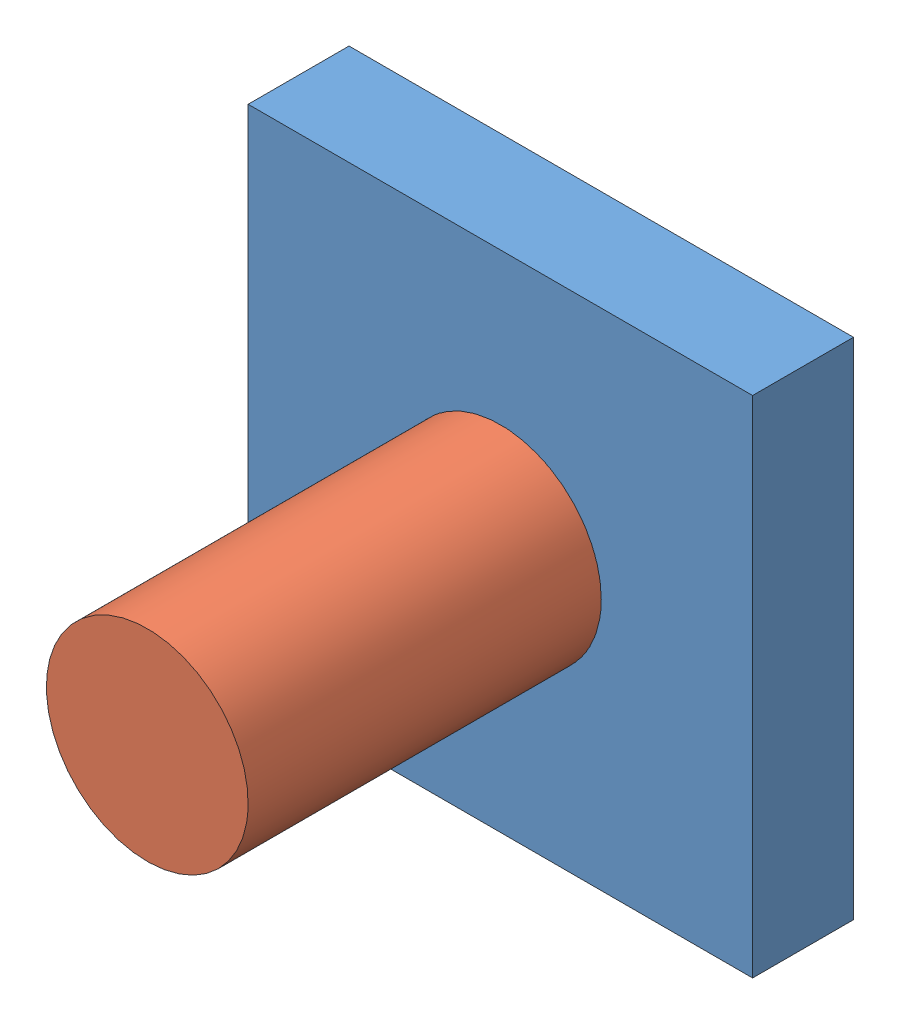
SolidWorks assembly Assem1, configuration Default. Lengths in mm.
Overall size (100 100 90).
2 component instances, 2 part files, 2 mates.
Components (placement in the parent):
- base-mpang-1: base-mpang [Default] at (17.5633 62.8483 79.9436) size (100 100 20)
- rod2-mpang-2: rod2-mpang [Default] at (17.5633 62.8483 89.9436) x (0.995036 -0.099515 0) z (0 0 1) size (40 40 80)
Mates (geometry in assembly coordinates):
- Coincident1: coincident: circle of base-mpang-1; circle of rod2-mpang-2
- Lock1: lock: unknown of base-mpang-1; unknown of rod2-mpang-2
